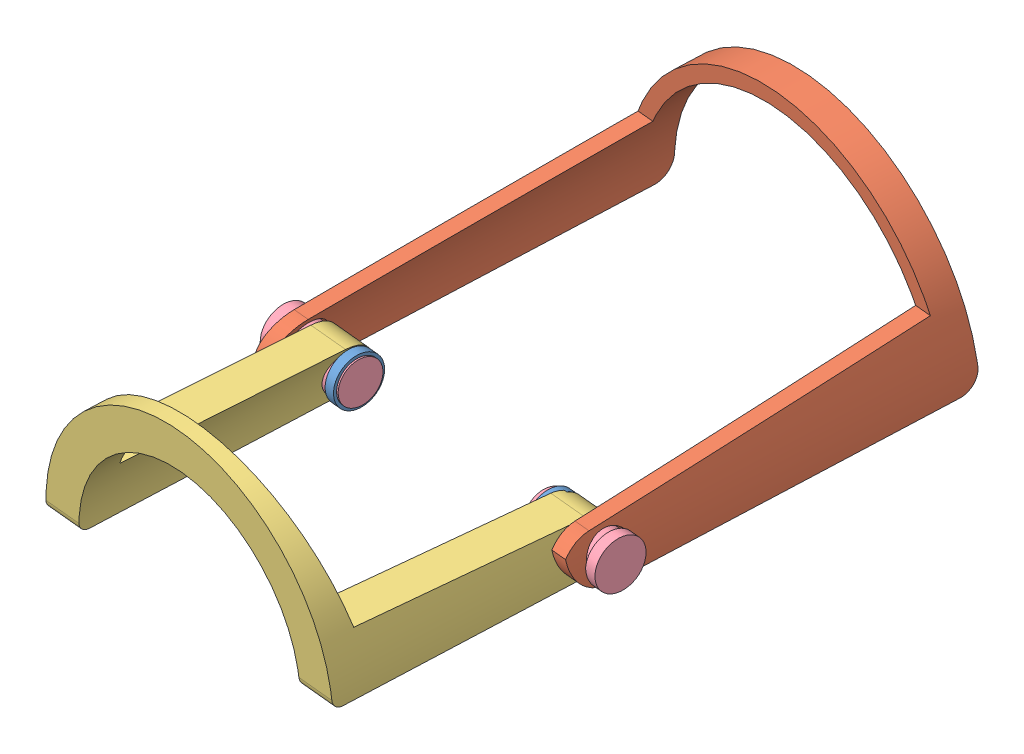
SolidWorks assembly Ensamblaje2, configuration Predeterminado. Lengths in mm.
Overall size (213.35 112.19 329.45).
6 component instances, 4 part files, 7 mates.
Components (placement in the parent):
- Pieza4-1: Pieza4 [Predeterminado] at (-143.8812 -67.315 99.4854) x (0.09738 -0.186994 -0.977523) z (0.995129 0.003134 0.098535) size (25 25 5)
- Pieza4-2: Pieza4 [Predeterminado] at (-20.2667 -66.9257 111.7254) x (-0.06685 -0.713151 0.697816) z (-0.995129 -0.003134 -0.098535) size (25 25 5)
- Pieza1-1: Pieza1 [Predeterminado] at (-65.3476 -68.3478 -73.246) x (0.995129 0.003134 0.098535) z (-0.098221 -0.054264 0.993684) size (190 95 200)
- Pieza2-4: Pieza2 [Predeterminado] at (-80.9689 -76.9781 84.793) x (0.995129 0.003134 0.098535) z (-0.098221 -0.054264 0.993684) size (170.79 85.39 144.03)
- Pieza3buena-3: Pieza3buena [Predeterminado] at (16.2611 -66.8107 115.3422) x (-0.098583 0.026216 0.994783) z (-0.995129 -0.003134 -0.098535) size (25 25 44.62)
- Pieza3buena-4: Pieza3buena [Predeterminado] at (-182.4268 -67.4364 95.6687) x (0.064415 -0.777295 -0.625829) z (0.995129 0.003134 0.098535) size (25 25 44.62)
Mates (geometry in assembly coordinates):
- Paralelo3: parallel aligned: cylinder of Pieza1-1 through (-84.9917 -79.2006 125.4908) axis (0.098221 0.054264 -0.993684) radius 87.0131; cylinder of Pieza2-4 through (-95.7021 -85.1177 233.8456) axis (0.098221 0.054264 -0.993684) radius 85.394
- Concéntrica1: concentric aligned: cylinder of Pieza1-1 through (-84.9917 -79.2006 125.4908) axis (0.098221 0.054264 -0.993684) radius 95; cylinder of Pieza2-4 through (-95.7021 -85.1177 233.8456) axis (0.098221 0.054264 -0.993684) radius 85.394
- Paralelo5: parallel aligned: cylinder of Pieza1-1 through (-205.5406 -65.2262 94.2111) axis (0.995129 0.003134 0.098535) radius 10.968; cylinder of Pieza2-4 through (-350.7408 -67.9664 79.0028) axis (0.995129 0.003134 0.098535) radius 10.7247
- Concéntrica5: concentric aligned: cylinder of Pieza2-4 through (215.4874 -66.1833 135.069) axis (-0.995129 -0.003134 -0.098535) radius 10.7247; cylinder of Pieza3buena-3 through (10.6695 -66.8283 114.7886) axis (-0.995129 -0.003134 -0.098535) radius 10.97
- Concéntrica7: concentric aligned: cylinder of Pieza2-4 through (-350.7408 -67.9664 79.0028) axis (0.995129 0.003134 0.098535) radius 10.7247; cylinder of Pieza3buena-4 through (-176.8352 -67.4188 96.2224) axis (0.995129 0.003134 0.098535) radius 10.97
- Concéntrica8: concentric anti-aligned: circle of Pieza4-1; cylinder of Pieza3buena-4 through (-176.8352 -67.4188 96.2224) axis (0.995129 0.003134 0.098535) radius 10.97
- Concéntrica9: concentric anti-aligned: circle of Pieza4-2; cylinder of Pieza3buena-3 through (10.6695 -66.8283 114.7886) axis (-0.995129 -0.003134 -0.098535) radius 10.97
